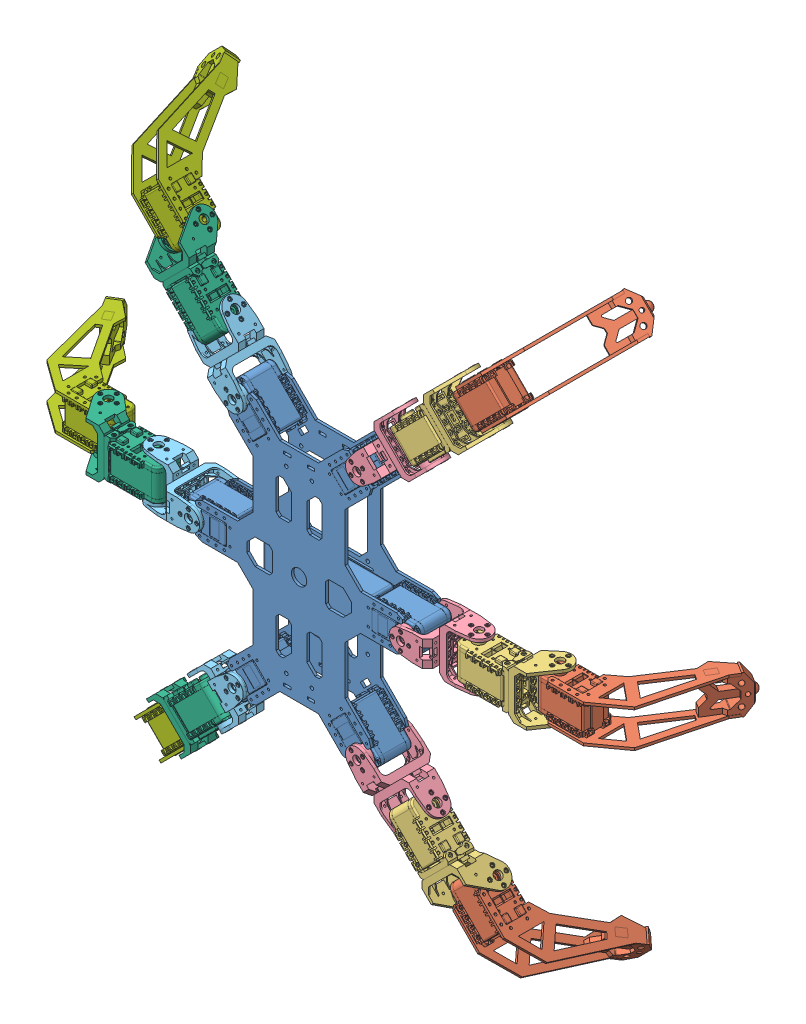
SolidWorks assembly Hexapod_allleg, configuration Default. Lengths in mm.
Overall size (636.88 582.72 145.5).
25 component instances, 7 part files, 16 mates.
Components (placement in the parent):
- Main_body-1: Main_body [Default] at origin size (230.08 274.24 38.67)
- Left_Leg-1: Left_Leg [Default] at (60.9101 -121.9101 -2.6) x (-0.707107 -0.707107 0) z (0 0 1) size (49.4 225.94 139)
  - Tibia_left-3: Tibia_left [Default] at (15.2 117.5 -28.8423) x (0 0 1) z (1 0 0) size (117.7 108.98 38.67)
  - Femur_left-3: Femur_left [Default] at (14.2997 53 -14.2997) x (0 0 1) z (1 0 0) size (42.04 87.04 48.5)
  - Coxa_left-3: Coxa_left [Default] at origin size (48.5 75 48.5)
- Right_Leg-1: Right_Leg [Default] at (-60.9101 -121.9101 -2.6) x (-0.707107 0.707107 0) z (0 0 1) size (49.4 225.94 145.5)
  - Coxa_right-1: Coxa_right [Default] at origin size (48.5 75 48.5)
  - Femur_right-1: Femur_right [Default] at (-14.3003 53 -14.2997) x (0 0 -1) z (-1 0 0) size (42.04 87.04 48.5)
  - Tibia_right-1: Tibia_right [Default] at (-15.2 117.5 -34.3423) x (0 0 -1) z (-1 0 0) size (117.7 108.98 38.67)
- Left_Leg-3: Left_Leg [Default] at (103.5 0 -2.6) x (0 -1 0) z (0 0 1) size (49.4 225.94 139)
  - Tibia_left-3: Tibia_left [Default] at (15.2 117.5 -28.8423) x (0 0 1) z (1 0 0) size (117.7 108.98 38.67)
  - Femur_left-3: Femur_left [Default] at (14.2997 53 -14.2997) x (0 0 1) z (1 0 0) size (42.04 87.04 48.5)
  - Coxa_left-3: Coxa_left [Default] at origin size (48.5 75 48.5)
- Left_Leg-4: Left_Leg [Default] at (60.9101 121.9101 -2.6) x (0.707107 -0.707107 0) z (0 0 1) size (49.4 225.94 139)
  - Tibia_left-3: Tibia_left [Default] at (15.2 117.5 -28.8423) x (0 0 1) z (1 0 0) size (117.7 108.98 38.67)
  - Femur_left-3: Femur_left [Default] at (14.2997 53 -14.2997) x (0 0 1) z (1 0 0) size (42.04 87.04 48.5)
  - Coxa_left-3: Coxa_left [Default] at origin size (48.5 75 48.5)
- Right_Leg-2: Right_Leg [Default] at (-103.5 0 -2.6) x (0 1 0) z (0 0 1) size (49.4 225.94 145.5)
  - Coxa_right-1: Coxa_right [Default] at origin size (48.5 75 48.5)
  - Femur_right-1: Femur_right [Default] at (-14.3003 53 -14.2997) x (0 0 -1) z (-1 0 0) size (42.04 87.04 48.5)
  - Tibia_right-1: Tibia_right [Default] at (-15.2 117.5 -34.3423) x (0 0 -1) z (-1 0 0) size (117.7 108.98 38.67)
- Right_Leg-3: Right_Leg [Default] at (-60.9101 121.9101 -2.6) x (0.707107 0.707107 0) z (0 0 1) size (49.4 225.94 145.5)
  - Coxa_right-1: Coxa_right [Default] at origin size (48.5 75 48.5)
  - Femur_right-1: Femur_right [Default] at (-14.3003 53 -14.2997) x (0 0 -1) z (-1 0 0) size (42.04 87.04 48.5)
  - Tibia_right-1: Tibia_right [Default] at (-15.2 117.5 -34.3423) x (0 0 -1) z (-1 0 0) size (117.7 108.98 38.67)
Mates (geometry in assembly coordinates):
- Parallel1: parallel aligned: plane of Main_body-1 through (156.2424 141.9391 293.4318) normal (-0.707107 0 0.707107); plane of ? through (199.934 132.1191 336.4174) normal (-0.707107 0 0.707107)
- Coincident17: coordinate: point of Main_body-1; point of assembly
- Coincident18: coordinate: unknown of Right_Leg-1/Coxa_right-1
- Coincident19: coordinate: unknown of Left_Leg-1/Coxa_left-3
- Concentric1: concentric anti-aligned: cylinder of Main_body-1 through (103.5 0 -2.6) axis (0 0 1) radius 4.6; cone of Left_Leg-3/Coxa_left-3 through (103.5 0 0.26) axis (0 0 -1)
- Parallel2: parallel aligned: plane of Main_body-1 through (68.71 -13 -31.08) normal (0 -1 0); plane of Left_Leg-3/Coxa_left-3 through (130 -12.5008 -40.9) normal (0 -1 0)
- Coincident21: coincident anti-aligned: plane of Main_body-1 through (98.716 4.784 -2.6) normal (0 0 1); plane of Left_Leg-3/Coxa_left-3 through (99.3309 4.1735 -2.6) normal (0 0 -1)
- Concentric2: concentric anti-aligned: cylinder of Main_body-1 through (60.9101 121.9101 -2.6) axis (0 0 1) radius 4.6; cone of Left_Leg-4/Coxa_left-3 through (60.9101 121.9101 0.26) axis (0 0 -1)
- Parallel3: parallel aligned: plane of Main_body-1 through (45.5022 88.1174 -31.08) normal (0.707107 -0.707107 0); plane of Left_Leg-4/Coxa_left-3 through (88.4878 131.809 -40.9) normal (0.707107 -0.707107 0)
- Coincident23: coincident anti-aligned: plane of Main_body-1 through (54.1445 121.9101 -2.6) normal (0 0 1); plane of Left_Leg-4/Coxa_left-3 through (55.011 121.9132 -2.6) normal (0 0 -1)
- Concentric3: concentric anti-aligned: cylinder of Main_body-1 through (-103.5 0 -2.6) axis (0 0 1) radius 4.6; cone of Right_Leg-2/Coxa_right-1 through (-103.5 0 0.26) axis (0 0 -1)
- Parallel4: parallel aligned: plane of Main_body-1 through (-68.71 13 -31.08) normal (0 1 0); plane of Right_Leg-2/Coxa_right-1 through (-130 12.5008 -40.9) normal (0 1 0)
- Coincident25: coincident anti-aligned: plane of Main_body-1 through (-98.716 -4.784 -2.6) normal (0 0 1); plane of Right_Leg-2/Coxa_right-1 through (-99.3309 -4.1735 -2.6) normal (0 0 -1)
- Concentric4: concentric: cylinder of Main_body-1 through (-60.9101 121.9101 -2.6) axis (0 0 1) radius 4.6; cone of Right_Leg-3/Coxa_right-1 through (-60.9101 121.9101 0.26) axis (0 0 -1)
- Parallel5: parallel: plane of Main_body-1 through (-27.1174 106.5022 -31.08) normal (0.707107 0.707107 0); plane of Right_Leg-3/Coxa_right-1 through (-70.809 149.4878 -40.9) normal (0.707107 0.707107 0)
- Coincident27: coincident anti-aligned: plane of Main_body-1 through (-60.9101 115.1445 -2.6) normal (0 0 1); plane of Right_Leg-3/Coxa_right-1 through (-60.9132 116.011 -2.6) normal (0 0 -1)
